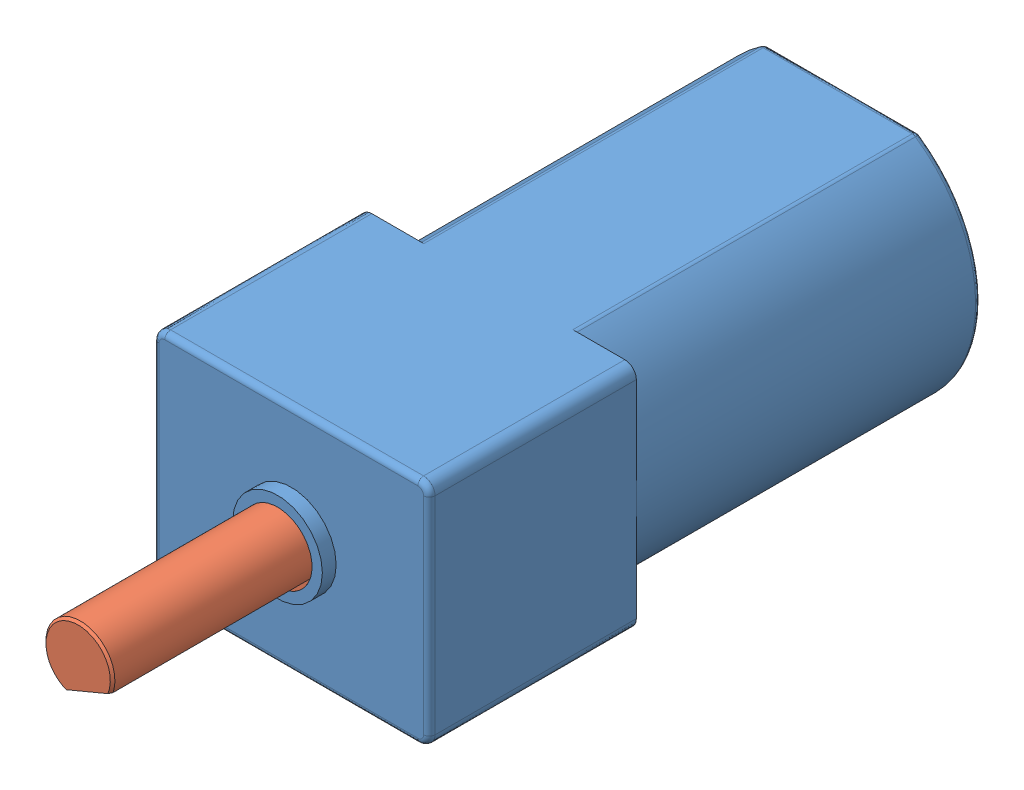
SolidWorks assembly User Library-Polulu Microgear Motor, configuration По умолчанию. Lengths in mm.
Overall size (12 10 35.27).
2 component instances, 2 part files, 1 mates.
Components (placement in the parent):
- User Library-Polulu Microgear Motor_VARIKL KORP-1: User Library-Polulu Microgear Motor_VARIKL KORP [По умолчанию] at (-82.4585 46.8312 -11) size (12 10 26.6)
- User Library-Polulu Microgear Motor_VARIKL ASIS-1: User Library-Polulu Microgear Motor_VARIKL ASIS [По умолчанию] at (-82.4585 46.8312 13.6) x (0.385529 -0.922696 0) z (0 0 -1) size (3 3 35.27)
Mates (geometry in assembly coordinates):
- Совпадение1: coincident: circle of User Library-Polulu Microgear Motor_VARIKL KORP-1; circle of User Library-Polulu Microgear Motor_VARIKL ASIS-1
